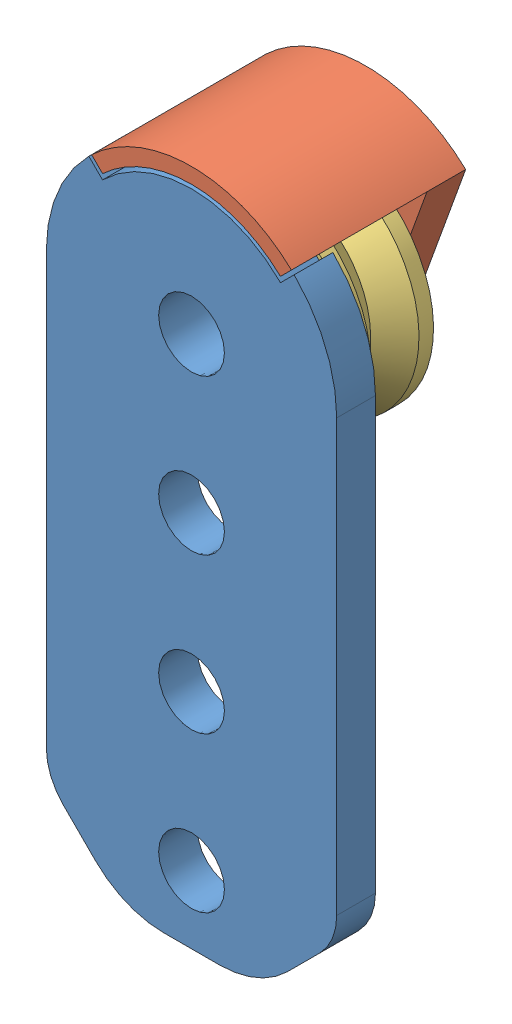
SolidWorks assembly PulleyMountSlides, configuration Default. Lengths in mm.
Overall size (15 35 9).
3 component instances, 3 part files, 6 mates.
Components (placement in the parent):
- pulleyCover2-1: pulleyCover2 [Default] at (4.8643 33.9192 29.7688) size (15 34 2.5)
- PulleyCoverSlide-1: PulleyCoverSlide [Default] at (4.8643 33.9192 29.7688) x (-1 0 0) z (0 0 -1) size (10.32 10.5 9)
- REV-41-1368.step-1: REV-41-1368.step [Default] at (4.8643 33.9192 27.2688) size (12 12 4)
Mates (geometry in assembly coordinates):
- InPlace1: in place: plane of pulleyCover2-1 through (4.8643 33.9192 29.7688) normal (0 0 -1); plane of ? through (0 0 29.7688) normal (0 0 -1); moOrthogonalPlaneRef_w of pulleyCover2-1 through (4.8643 33.9192 29.7688) normal (0 0 -1); plane of ? through (0 0 29.7688) normal (0 1 0); plane of pulleyCover2-1 through (4.8643 33.9192 29.7688) normal (0 0 -1); plane of ? through (0 0 29.7688) normal (-1 0 0); plane of pulleyCover2-1 through (4.8643 33.9192 29.7688) normal (0 0 -1); unknown of PulleyCoverSlide-1
- Coincident1: coincident: plane of pulleyCover2-1; plane of PulleyCoverSlide-1
- Coincident2: coincident: moOrthogonalPlaneRef_w of pulleyCover2-1 through (4.8643 33.9192 29.7688) normal (0 1 0); plane of PulleyCoverSlide-1 through (4.8643 33.9192 29.7688) normal (0 1 0)
- Coincident3: coincident: moOrthogonalPlaneRef_w of pulleyCover2-1 through (4.8643 33.9192 29.7688) normal (1 0 0); plane of PulleyCoverSlide-1 through (4.8643 33.9192 29.7688) normal (-1 0 0)
- Coincident4: coincident: plane of pulleyCover2-1 through (4.8643 33.9192 29.2688) normal (0 0 -1); plane of REV-41-1368.step-1 through (4.8643 35.9692 29.2688) normal (0 0 1)
- Concentric1: concentric: cylinder of pulleyCover2-1 through (4.8643 33.9192 31.7688) axis (0 0 -1) radius 1.7; cylinder of REV-41-1368.step-1 through (4.8643 33.9192 27.2688) axis (0 0 -1) radius 1.55
